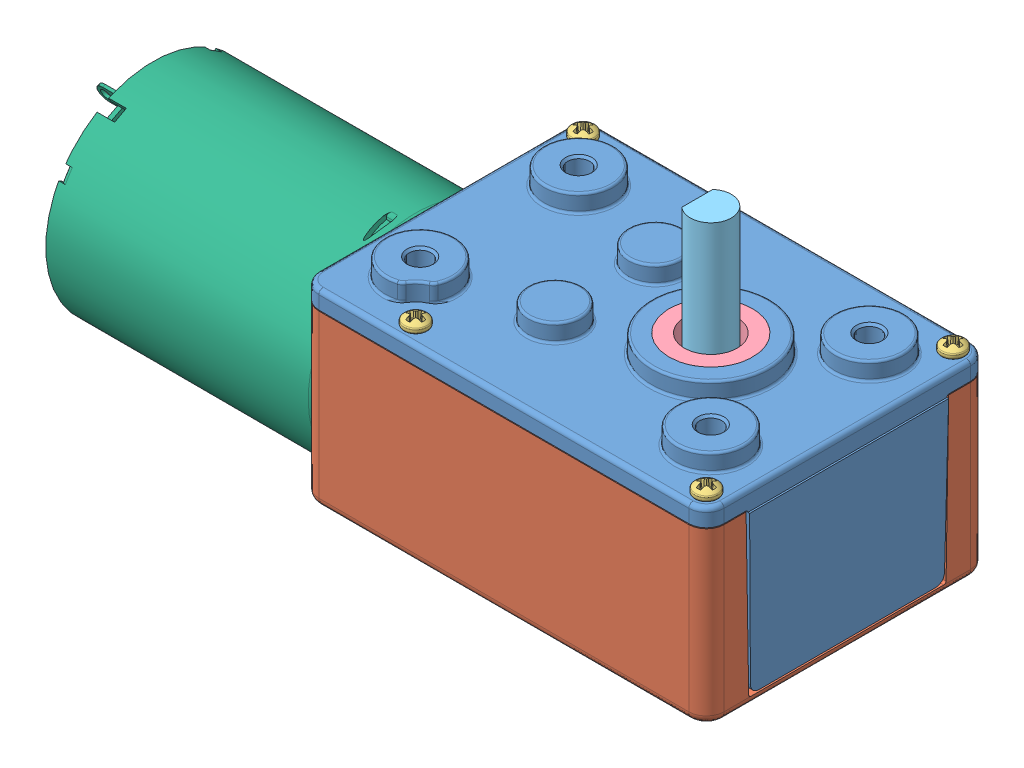
SolidWorks assembly Amazon-gearmotor, configuration Default. Lengths in mm.
Overall size (121.88 63.37 48.95).
9 component instances, 6 part files, 19 mates.
Components (placement in the parent):
- gearbox-case-output-2: gearbox-case-output [Default] at (26.6557 27.7252 36.633) size (69.3 33.45 48)
- gearbox-case-input-1: gearbox-case-input [Default] at (22.1496 2.1331 36.8616) size (69 32.25 48)
- M2-04-6-92000A013_18-8 SS METRIC PAN HEAD PHIL MACHINE SCREW-1: M2-04-6-92000A013_18-8 SS METRIC PAN HEAD PHIL MACHINE SCREW [92000A013] at (-14.5355 25.1047 15.6352) x (1 0 0) z (0 1 0) size (4 4 7.68)
- M2-04-6-92000A013_18-8 SS METRIC PAN HEAD PHIL MACHINE SCREW-2: M2-04-6-92000A013_18-8 SS METRIC PAN HEAD PHIL MACHINE SCREW [92000A013] at (-1.0355 25.1047 57.6352) x (1 0 0) z (0 1 0) size (4 4 7.68)
- M2-04-6-92000A013_18-8 SS METRIC PAN HEAD PHIL MACHINE SCREW-3: M2-04-6-92000A013_18-8 SS METRIC PAN HEAD PHIL MACHINE SCREW [92000A013] at (48.4645 25.1047 15.6352) x (1 0 0) z (0 1 0) size (4 4 7.68)
- M2-04-6-92000A013_18-8 SS METRIC PAN HEAD PHIL MACHINE SCREW-4: M2-04-6-92000A013_18-8 SS METRIC PAN HEAD PHIL MACHINE SCREW [92000A013] at (48.4645 25.1047 57.6352) x (1 0 0) z (0 1 0) size (4 4 7.68)
- Amazon-gearmotor-bushing-1: Amazon-gearmotor-bushing [Default] at (28.2145 28.6893 36.6352) size (18 7.5 18)
- Amazon-gearmotor-shaft-1: Amazon-gearmotor-shaft [Default] at (28.2145 27.8047 36.6352) x (-1 0 0) z (0 0 -1) size (7 25 7)
- Amazon-gearmotor-motor-1: Amazon-gearmotor-motor [Default] at (-58.1724 11.3778 39.6357) x (0 0.224951 -0.97437) z (0 -0.97437 -0.224951) size (36.6 75.83 36.6)
Mates (geometry in assembly coordinates):
- Concentric1: concentric anti-aligned: cylinder of gearbox-case-output-2 through (48.4645 28.1047 57.6352) axis (0 -1 0) radius 1.8; cylinder of gearbox-case-input-1 through (48.4645 28.1047 57.6352) axis (0 1 0) radius 1.2
- Concentric2: concentric anti-aligned: cylinder of gearbox-case-output-2 through (-14.5355 28.1047 15.6352) axis (0 -1 0) radius 1.8; cylinder of gearbox-case-input-1 through (-14.5355 28.1047 15.6352) axis (0 1 0) radius 1.2
- Coincident1: coincident anti-aligned: plane of gearbox-case-output-2 through (48.4645 28.1047 15.6352) normal (0 -1 0); plane of gearbox-case-input-1 through (48.4645 28.1047 15.6352) normal (0 1 0)
- Coincident2: coincident anti-aligned: plane of gearbox-case-output-2 through (48.4645 31.1047 15.6352) normal (0 1 0); plane of M2-04-6-92000A013_18-8 SS METRIC PAN HEAD PHIL MACHINE SCREW-1 through (-14.5355 31.1047 15.6352) normal (0 -1 0)
- Concentric3: concentric anti-aligned: circle of gearbox-case-output-2; circle of M2-04-6-92000A013_18-8 SS METRIC PAN HEAD PHIL MACHINE SCREW-1
- Coincident3: coincident anti-aligned: plane of gearbox-case-output-2 through (48.4645 31.1047 15.6352) normal (0 1 0); plane of M2-04-6-92000A013_18-8 SS METRIC PAN HEAD PHIL MACHINE SCREW-2 through (-1.0355 31.1047 57.6352) normal (0 -1 0)
- Coincident4: coincident anti-aligned: plane of gearbox-case-output-2 through (48.4645 31.1047 15.6352) normal (0 1 0); plane of M2-04-6-92000A013_18-8 SS METRIC PAN HEAD PHIL MACHINE SCREW-3 through (48.4645 31.1047 15.6352) normal (0 -1 0)
- Coincident5: coincident anti-aligned: plane of gearbox-case-output-2 through (48.4645 31.1047 15.6352) normal (0 1 0); plane of M2-04-6-92000A013_18-8 SS METRIC PAN HEAD PHIL MACHINE SCREW-4 through (48.4645 31.1047 57.6352) normal (0 -1 0)
- Concentric4: concentric anti-aligned: circle of gearbox-case-output-2; circle of M2-04-6-92000A013_18-8 SS METRIC PAN HEAD PHIL MACHINE SCREW-2
- Concentric5: concentric anti-aligned: circle of gearbox-case-output-2; circle of M2-04-6-92000A013_18-8 SS METRIC PAN HEAD PHIL MACHINE SCREW-4
- Concentric6: concentric anti-aligned: circle of gearbox-case-output-2; circle of M2-04-6-92000A013_18-8 SS METRIC PAN HEAD PHIL MACHINE SCREW-3
- Coincident6: coincident aligned: circle of gearbox-case-output-2; plane of Amazon-gearmotor-bushing-1 through (28.2145 28.1047 36.6352) normal (0 1 0)
- Concentric7: concentric aligned: circle of gearbox-case-output-2; circle of Amazon-gearmotor-bushing-1
- Distance1: distance = 18.7 mm aligned: plane of Amazon-gearmotor-shaft-1 through (28.2145 52.8047 36.6352) normal (0 1 0); plane of gearbox-case-output-2 through (28.2145 34.1047 36.6352) normal (0 1 0)
- Concentric8: concentric aligned: cylinder of Amazon-gearmotor-bushing-1 through (28.2145 34.1047 36.6352) axis (0 -1 0) radius 4.5015; cylinder of Amazon-gearmotor-shaft-1 through (28.2145 52.8047 36.6352) axis (0 -1 0) radius 3.5
- Coincident8: coincident anti-aligned: plane of gearbox-case-input-1 through (-17.5355 28.1047 15.6352) normal (-1 0 0); plane of Amazon-gearmotor-motor-1 through (-17.5355 11.3797 39.6352) normal (1 0 0)
- Concentric9: concentric anti-aligned: circle of gearbox-case-input-1; circle of Amazon-gearmotor-motor-1
- Concentric10: concentric anti-aligned: circle of gearbox-case-input-1; circle of Amazon-gearmotor-motor-1
- Parallel1: parallel aligned: plane of gearbox-case-input-1 through (-17.5355 28.1047 15.6352) normal (-1 0 0); plane of Amazon-gearmotor-shaft-1 through (25.9145 52.8047 33.1352) normal (-1 0 0)
